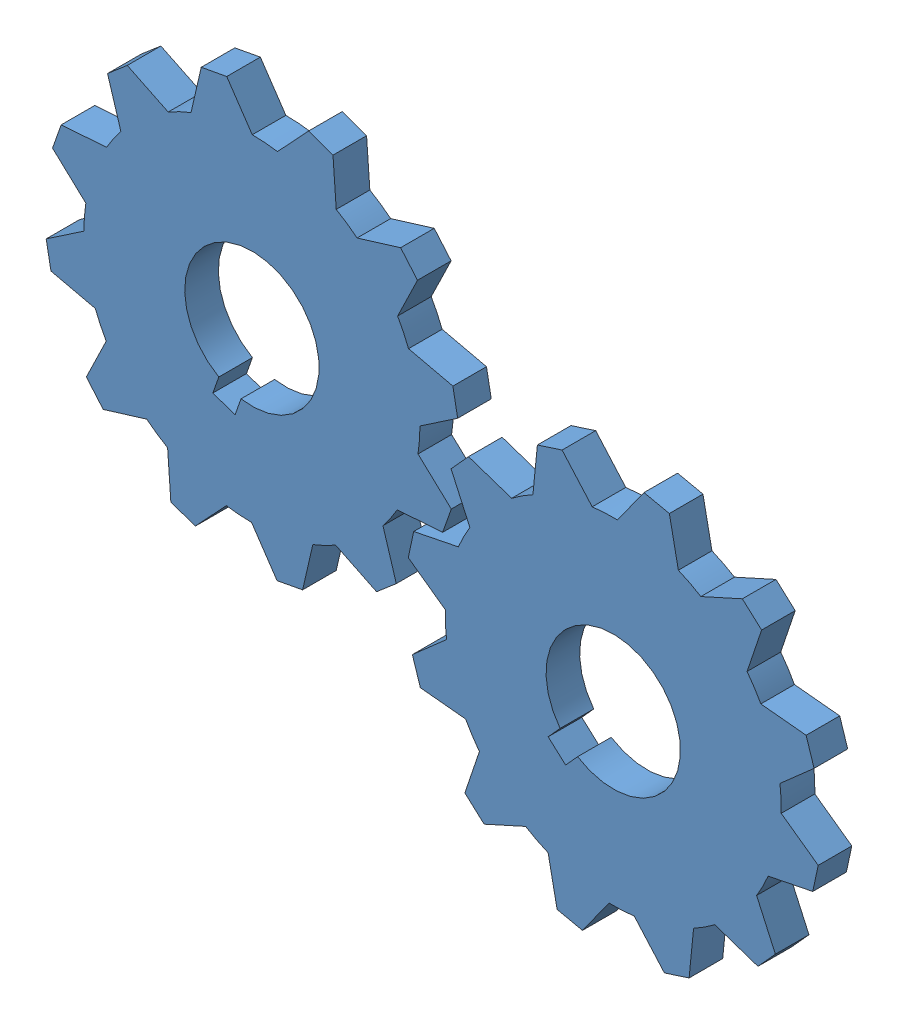
SolidWorks assembly Test_4_Respaldo, configuration Default. Lengths in mm.
Overall size (272.98 210.38 10).
2 component instances, 1 part files, 4 mates.
Components (placement in the parent):
- Gear_1-3: Gear_1 [Default] at (-105.6577 26.5914 -10) x (0.741736 -0.670692 0) z (0 0 1) size (123.1 123.1 10)
- Gear_1-4: Gear_1 [Default] at (-213.1724 71.5073 -10) x (0.943021 -0.332734 0) z (0 0 1) size (123.1 123.1 10)
Mates (geometry in assembly coordinates):
- Coincident1: coincident aligned: plane of Gear_1-4 through (-213.1724 71.5073 0) normal (0 0 1)
- Coincident2: coincident aligned: plane of Gear_1-3 through (-105.6577 26.5914 0) normal (0 0 1)
- Concentric1: concentric anti-aligned: circle of Gear_1-4
- Concentric2: concentric anti-aligned: circle of Gear_1-3
